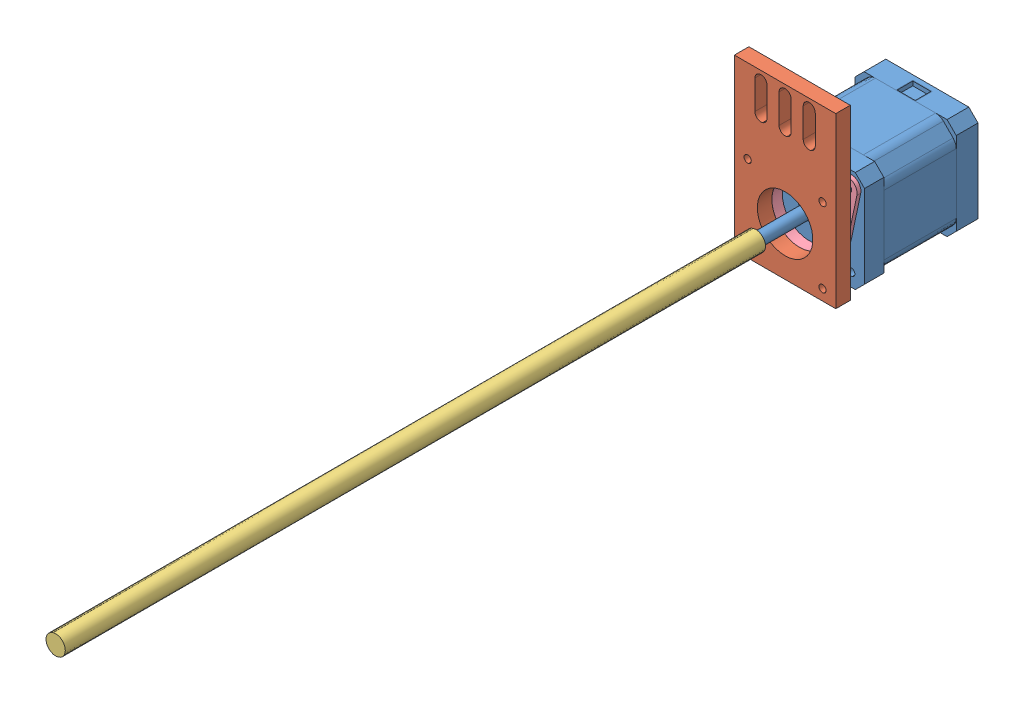
SolidWorks assembly Z Stepper, configuration Default. Lengths in mm.
Overall size (93.79 93.79 362).
4 component instances, 4 part files, 8 mates.
Components (placement in the parent):
- NEMA17_48-1: NEMA17_48 [Default] at (26.3685 35.4579 55.652) size (42 42 71)
- Z Stepper Mount-1: Z Stepper Mount [Default] at (26.3685 50.4579 67.552) x (1 0 0) z (0 1 0) size (42 6 70)
- 8mm TR8_8 Leadscrew-1: 8mm TR8_8 Leadscrew [250mm - 8mm TR8_8 Leadscrew] at (26.3685 35.4579 369.652) size (8 8 291)
- Stepper Damper-1: Stepper Damper [Default] at (26.3688 35.4581 55.652) x (0.707107 -0.707107 0) z (-0.707107 -0.707107 0) size (51.85 6.11 80.79)
Mates (geometry in assembly coordinates):
- Concentric1: concentric aligned: cylinder of NEMA17_48-1 through (41.8685 50.9579 51.152) axis (0 0 1) radius 1.5; cylinder of Z Stepper Mount-1 through (41.8685 50.9579 61.552) axis (0 0 1) radius 1.55
- Concentric2: concentric aligned: cylinder of NEMA17_48-1 through (10.8685 19.9579 51.152) axis (0 0 1) radius 1.5; cylinder of Z Stepper Mount-1 through (10.8685 19.9579 61.552) axis (0 0 1) radius 1.55
- Coincident2: coincident anti-aligned: plane of NEMA17_48-1 through (26.3685 35.4579 79.652) normal (0 0 1); plane of 8mm TR8_8 Leadscrew-1 through (26.3685 35.4579 79.652) normal (0 0 -1)
- Concentric3: concentric anti-aligned: cylinder of NEMA17_48-1 through (26.3685 35.4579 79.652) axis (0 0 -1) radius 2.5; cylinder of 8mm TR8_8 Leadscrew-1 through (26.3685 35.4579 79.652) axis (0 0 1) radius 4
- Coincident3: coincident anti-aligned: plane of NEMA17_48-1 through (26.3685 35.4579 55.652) normal (0 0 1); plane of Stepper Damper-1 through (26.3688 35.4581 55.652) normal (0 0 -1)
- Concentric4: concentric anti-aligned: cylinder of NEMA17_48-1 through (10.8685 19.9579 51.152) axis (0 0 1) radius 1.5; cylinder of Stepper Damper-1 through (10.869 19.9583 55.652) axis (0 0 -1) radius 1.75
- Concentric5: concentric anti-aligned: cylinder of NEMA17_48-1 through (41.8685 50.9579 51.152) axis (0 0 1) radius 1.5; cylinder of Stepper Damper-1 through (41.8685 50.9579 55.652) axis (0 0 -1) radius 1.75
- Coincident4: coincident: plane of Z Stepper Mount-1 through (26.3685 50.4579 61.552) normal (0 0 -1); line of Stepper Damper-1 through (45.7839 20.7769 61.552) axis (-0.204634 0.978839 0)
